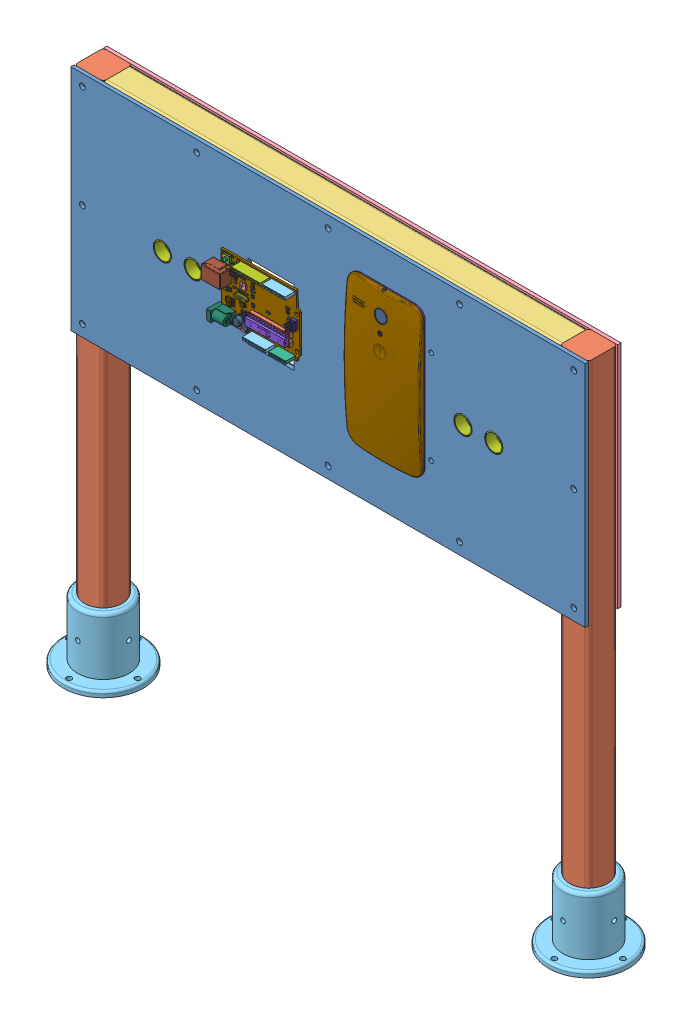
SolidWorks assembly Smart Muisc Player, configuration Default. Lengths in mm.
Overall size (494.6 455 70).
116 component instances, 48 part files, 30 mates.
Components (placement in the parent):
- Front Panel-1: Front Panel [Default] at (-41.307 7.8508 14.9634) size (450 200 3)
- Vetical stand-1: Vetical stand [Default] at (170.993 -341.5339 2.2634) size (25.4 450 25.4)
- Vetical stand-2: Vetical stand [Default] at (-253.607 -341.5339 2.2634) size (25.4 450 25.4)
- Horizontal Stand-2: Horizontal Stand [Default] at (-240.907 95.7661 2.2634) size (399.2 25.4 25.4)
- Horizontal Stand-3: Horizontal Stand [Default] at (-240.907 -78.8339 2.2634) size (399.2 25.4 25.4)
- Back Panel-1: Back Panel [Default] at (-41.307 8.4661 -13.4366) size (450 200 3)
- Base-1: Base [Default] at (170.993 -346.5339 2.2634) size (70 55 70)
- Base-2: Base [Default] at (-253.607 -346.5339 2.2634) size (70 55 70)
- Assem3_1-1: Assem3_1 [Default] at (-169.9461 10.2657 10.8902) x (1 0 0) z (0 -1 0) size (45 18.3 26.12)
  - pin header-1: pin header [Default] at (-4.1109 -10.7267 50.9724) x (0 0 -1) z (1 0 0) size (7.62 4.5 1)
  - UltraSonic-1: UltraSonic [Default] at (-2.8609 -7.9267 1.7996) size (45 15 20)
  - pin header-2: pin header [Default] at (0.8891 -10.7267 50.9724) x (0 0 -1) z (1 0 0) size (7.62 4.5 1)
  - part2_1-1: part2_1 [Default] at (-16.3609 -2.9267 1.7996) x (0.862539 0 -0.505991) z (0.505991 0 0.862539) size (8 0.65 8)
  - pin header-3: pin header [Default] at (-6.6109 -10.7267 50.9724) x (0 0 -1) z (1 0 0) size (7.62 4.5 1)
  - pin header-4: pin header [Default] at (-1.6109 -10.7267 50.9724) x (0 0 -1) z (1 0 0) size (7.62 4.5 1)
  - part2_1-2: part2_1 [Default] at (10.6391 -2.6926 1.7996) x (0.988186 0 -0.153259) z (0.153259 0 0.988186) size (8 0.65 8)
- Assem3_1-2: Assem3_1 [Default] at (93.0539 10.2657 10.8902) x (1 0 0) z (0 -1 0) size (45 18.3 26.12)
  - pin header-1: pin header [Default] at (-4.1109 -10.7267 50.9724) x (0 0 -1) z (1 0 0) size (7.62 4.5 1)
  - UltraSonic-1: UltraSonic [Default] at (-2.8609 -7.9267 1.7996) size (45 15 20)
  - pin header-2: pin header [Default] at (0.8891 -10.7267 50.9724) x (0 0 -1) z (1 0 0) size (7.62 4.5 1)
  - part2_1-1: part2_1 [Default] at (-16.3609 -2.9267 1.7996) x (0.862539 0 -0.505991) z (0.505991 0 0.862539) size (8 0.65 8)
  - pin header-3: pin header [Default] at (-6.6109 -10.7267 50.9724) x (0 0 -1) z (1 0 0) size (7.62 4.5 1)
  - pin header-4: pin header [Default] at (-1.6109 -10.7267 50.9724) x (0 0 -1) z (1 0 0) size (7.62 4.5 1)
  - part2_1-2: part2_1 [Default] at (10.6391 -2.6926 1.7996) x (0.988186 0 -0.153259) z (0.153259 0 0.988186) size (8 0.65 8)
- arduino uno-2: arduino uno [Default] at (-131.6569 -13.9823 20.7834) x (0.013312 -0.999911 0) z (-0.999911 -0.013312 0) size (53.34 15.25 74.93)
  - unoboard blue-1: unoboard blue [Default] at origin size (53.34 1.65 68.58)
  - 47uf CAP Dcase-1: 47uf CAP Dcase [Default] at (-9.4141 0 -18.4991) x (0 0 -1) z (1 0 0) size (6.6 5.81 8)
  - USB SHELL-1: USB SHELL [Default] at (-38.02 0.43 6.35) size (13.72 15.2 16.51)
  - USB core-1: USB core [Default] at (-38.02 0.43 6.35) size (11.3 10.68 15.75)
  - usb top contact-1: usb top contact [Default] at (-36.77 6.52 5.97) size (1 9.67 13.76)
  - usb btm contact-1: usb btm contact [Default] at (-36.77 4.84 5.97) size (1 6.84 11.76)
  - usb btm contact-2: usb btm contact [Default] at (-39.27 4.84 5.97) size (1 6.84 11.76)
  - usb top contact-2: usb top contact [Default] at (-39.27 6.52 5.97) size (1 9.67 13.76)
  - power jack-1: power jack [Default] at (-7.675 0 1.905) size (11.2 15.2 15.9)
  - 47uf CAP Dcase-2: 47uf CAP Dcase [Default] at (-9.4141 0 -25.7132) x (0 0 -1) z (1 0 0) size (6.6 5.81 8)
  - crystal-1: crystal [Default] at (-26.162 0 -18.923) x (1 0 0) z (0 0 -1) size (4 5 11)
  - 2pin_header__02-1: 2pin_header__02 [Default] at (-46.23 0 -15.75) size (5 11.75 2.54)
  - nano - reg-1: nano - reg [Default] at (-17.399 0 -7.747) size (6.5 1.69 8.3)
  - led-1: led [Default] at (-34.29 0 -27.94) x (0 0 1) z (-1 0 0) size (4 0.9 1.55)
  - 2pin_header__02-2: 2pin_header__02 [Default] at (-30.43 0 -64.91) x (0 0 1) z (-1 0 0) size (5 11.75 2.54)
  - dip28-1: dip28 [Default] at (-16.383 1.5 -46.355) x (0 0 -1) z (1 0 0) size (35.48 2.8 10.1)
  - dip socket pin-1: dip socket pin [Default] at (-20.193 4.3 -62.865) x (0 0 -1) z (1 0 0) size (1.7 7.37 1.7)
  - dip socket pin-2: dip socket pin [Default] at (-12.573 4.3 -62.865) x (0 0 -1) z (1 0 0) size (1.7 7.37 1.7)
  - dip socket pin-3: dip socket pin [Default] at (-20.193 4.3 -60.325) x (0 0 -1) z (1 0 0) size (1.7 7.37 1.7)
  - dip socket pin-4: dip socket pin [Default] at (-12.573 4.3 -60.325) x (0 0 -1) z (1 0 0) size (1.7 7.37 1.7)
  - dip socket pin-5: dip socket pin [Default] at (-20.193 4.3 -57.785) x (0 0 -1) z (1 0 0) size (1.7 7.37 1.7)
  - dip socket pin-6: dip socket pin [Default] at (-12.573 4.3 -57.785) x (0 0 -1) z (1 0 0) size (1.7 7.37 1.7)
  - dip socket pin-7: dip socket pin [Default] at (-20.193 4.3 -55.245) x (0 0 -1) z (1 0 0) size (1.7 7.37 1.7)
  - dip socket pin-8: dip socket pin [Default] at (-12.573 4.3 -55.245) x (0 0 -1) z (1 0 0) size (1.7 7.37 1.7)
  - dip socket pin-9: dip socket pin [Default] at (-20.193 4.3 -52.705) x (0 0 -1) z (1 0 0) size (1.7 7.37 1.7)
  - dip socket pin-10: dip socket pin [Default] at (-12.573 4.3 -52.705) x (0 0 -1) z (1 0 0) size (1.7 7.37 1.7)
  - dip socket pin-11: dip socket pin [Default] at (-20.193 4.3 -50.165) x (0 0 -1) z (1 0 0) size (1.7 7.37 1.7)
  - dip socket pin-12: dip socket pin [Default] at (-12.573 4.3 -50.165) x (0 0 -1) z (1 0 0) size (1.7 7.37 1.7)
  - dip socket pin-13: dip socket pin [Default] at (-20.193 4.3 -47.625) x (0 0 -1) z (1 0 0) size (1.7 7.37 1.7)
  - dip socket pin-14: dip socket pin [Default] at (-12.573 4.3 -47.625) x (0 0 -1) z (1 0 0) size (1.7 7.37 1.7)
  - dip socket pin-15: dip socket pin [Default] at (-20.193 4.3 -45.085) x (0 0 -1) z (1 0 0) size (1.7 7.37 1.7)
  - dip socket pin-16: dip socket pin [Default] at (-12.573 4.3 -45.085) x (0 0 -1) z (1 0 0) size (1.7 7.37 1.7)
  - dip socket pin-17: dip socket pin [Default] at (-20.193 4.3 -42.545) x (0 0 -1) z (1 0 0) size (1.7 7.37 1.7)
  - dip socket pin-18: dip socket pin [Default] at (-12.573 4.3 -42.545) x (0 0 -1) z (1 0 0) size (1.7 7.37 1.7)
  - dip socket pin-19: dip socket pin [Default] at (-20.193 4.3 -40.005) x (0 0 -1) z (1 0 0) size (1.7 7.37 1.7)
  - dip socket pin-20: dip socket pin [Default] at (-12.573 4.3 -40.005) x (0 0 -1) z (1 0 0) size (1.7 7.37 1.7)
  - dip socket pin-21: dip socket pin [Default] at (-20.193 4.3 -37.465) x (0 0 -1) z (1 0 0) size (1.7 7.37 1.7)
  - dip socket pin-22: dip socket pin [Default] at (-12.573 4.3 -37.465) x (0 0 -1) z (1 0 0) size (1.7 7.37 1.7)
  - dip socket pin-23: dip socket pin [Default] at (-20.193 4.3 -34.925) x (0 0 -1) z (1 0 0) size (1.7 7.37 1.7)
  - dip socket pin-24: dip socket pin [Default] at (-12.573 4.3 -34.925) x (0 0 -1) z (1 0 0) size (1.7 7.37 1.7)
  - dip socket pin-25: dip socket pin [Default] at (-20.193 4.3 -32.385) x (0 0 -1) z (1 0 0) size (1.7 7.37 1.7)
  - dip socket pin-26: dip socket pin [Default] at (-12.573 4.3 -32.385) x (0 0 -1) z (1 0 0) size (1.7 7.37 1.7)
  - dip socket pin-27: dip socket pin [Default] at (-20.193 4.3 -29.845) x (0 0 -1) z (1 0 0) size (1.7 7.37 1.7)
  - dip socket pin-28: dip socket pin [Default] at (-12.573 4.3 -29.845) x (0 0 -1) z (1 0 0) size (1.7 7.37 1.7)
  - 2pin_header__02-3: 2pin_header__02 [Default] at (-27.89 0 -64.91) x (0 0 1) z (-1 0 0) size (5 11.75 2.54)
  - 2pin_header__02-4: 2pin_header__02 [Default] at (-25.35 0 -64.91) x (0 0 1) z (-1 0 0) size (5 11.75 2.54)
  - 2pin_header__02-5: 2pin_header__02 [Default] at (-46.23 0 -18.29) size (5 11.75 2.54)
  - 2pin_header__02-6: 2pin_header__02 [Default] at (-46.23 0 -20.83) size (5 11.75 2.54)
  - atmega16u2-1: atmega16u2 [Default] at (-34.671 0.06 -20) x (1 0 0) z (0 0 -1) size (5.5 1.01 5.5)
  - led-2: led [Default] at (-36.83 0 -27.94) x (0 0 1) z (-1 0 0) size (4 0.9 1.55)
  - led-3: led [Default] at (-42.037 0 -27.94) x (0 0 1) z (-1 0 0) size (4 0.9 1.55)
  - led-4: led [Default] at (-36.576 0 -58.42) x (0 0 1) z (-1 0 0) size (4 0.9 1.55)
  - 8 PORT HEADER-1: 8 PORT HEADER [Default] at (-50.8 0 -45.72) x (0 0 -1) z (1 0 0) size (20.32 10.51 2.41)
  - 8 PORT HEADER-2: 8 PORT HEADER [Default] at (-2.54 0 -27.94) x (0 0 -1) z (1 0 0) size (20.32 10.51 2.41)
  - 6 PORT HEADER-1: 6 PORT HEADER [Default] at (-2.54 0 -50.8) x (0 0 -1) z (1 0 0) size (15.24 10.51 2.41)
  - 10 PORT HEADER-1: 10 PORT HEADER [Default] at (-50.8 0 -18.796) x (0 0 -1) z (1 0 0) size (25.4 10.51 2.41)
  - ATMEL328P-1: ATMEL328P [Default] at (-16.383 4.3 -46.355) x (0 0 -1) z (1 0 0) size (35 7.27 7.87)
  - 102 RESISTOR PACK-1: 102 RESISTOR PACK [Default] at (-33.782 0 -58.42) size (3.2 0.51 3)
  - 102 RESISTOR PACK-2: 102 RESISTOR PACK [Default] at (-39.37 0 -27.94) size (3.2 0.51 3)
  - 103 RESISTOR PACK-1: 103 RESISTOR PACK [Default] at (-23.876 0 -27.94) size (3.2 0.51 3)
  - 220 RESISTOR PACK-1: 220 RESISTOR PACK [Default] at (-36.83 0 -12.827) size (3.2 0.51 3)
  - 16mhz crystal - measured-1: 16mhz crystal - measured [Default] at (-24.892 0 -41.275) x (0 0 -1) z (1 0 0) size (3.4 0.8 2)
  - PADS001-1: PADS001 [Default] at (-39.878 0.1 -18.288) x (-1 0 0) z (0 0 1) size (4.54 0.1 4.54)
  - 603 cap on pad-1: 603 cap on pad [Default] at (-44.45 0 -27.94) x (0 0 -1) z (1 0 0) size (2.76 0.91 1.02)
  - ssot3-1: ssot3 [Default] at (-26.5 0 -8.128) x (-1 0 0) z (0 0 -1) size (3 1.13 3.09)
  - mf-msmf050-2-1: mf-msmf050-2 [Default] at (-26.5 0 -4.064) size (5.76 1.02 3.72)
  - 603 cap on pad-2: 603 cap on pad [Default] at (-29.845 0 -27.94) x (0 0 -1) z (1 0 0) size (2.76 0.91 1.02)
  - 603 cap on pad-3: 603 cap on pad [Default] at (-31.496 0 -27.94) x (0 0 -1) z (1 0 0) size (2.76 0.91 1.02)
  - lmv358-1: lmv358 [Default] at (-15.24 0 -21.971) x (0 0 -1) z (1 0 0) size (3.7 1.4 2.9)
  - 603 cap on pad-4: 603 cap on pad [Default] at (-15.24 0 -18.415) size (2.76 0.91 1.02)
  - 603 cap on pad-5: 603 cap on pad [Default] at (-29.845 0 -12.065) x (0 0 1) z (-1 0 0) size (2.76 0.91 1.02)
  - 603 cap on pad-6: 603 cap on pad [Default] at (-29.591 0 -22.352) x (0 0 1) z (-1 0 0) size (2.76 0.91 1.02)
  - 603 cap on pad-7: 603 cap on pad [Default] at (-29.591 0 -16.002) x (0 0 1) z (-1 0 0) size (2.76 0.91 1.02)
  - 603 cap on pad-8: 603 cap on pad [Default] at (-41.91 0 -12.7) x (0 0 1) z (-1 0 0) size (2.76 0.91 1.02)
  - lp2985dgkr-1: lp2985dgkr [Default] at (-20.32 0 -19.05) x (0 0 -1) z (1 0 0) size (5.85 1.1 3)
  - cd1206 diode-1: cd1206 diode [Default] at (-27.94 0 -59.436) x (0 0 -1) z (1 0 0) size (2.09 0.96 5)
  - cd1206 diode-2: cd1206 diode [Default] at (-46.228 0 -13.081) x (0 0 1) z (-1 0 0) size (2.09 0.96 5)
  - 603 resistor-1: 603 resistor [Default] at (-29.591 0 -19.05) x (0 0 1) z (-1 0 0) size (2.36 0.62 1.03)
  - blm21-1: blm21 [Default] at (-45.085 0 -7.62) x (0 0 -1) z (1 0 0) size (2.78 0.95 1.32)
  - m7 diode-1: m7 diode [Default] at (-2.794 0 -21.59) x (0 0 -1) z (1 0 0) size (6.66 2.35 2.5)
  - MLC0603-1: MLC0603 [Default] at (-33.655 0 -12.827) x (0 0 -1) z (1 0 0) size (2.36 0.6 1.03)
  - MLC0603-2: MLC0603 [Default] at (-39.37 0 -12.827) x (0 0 -1) z (1 0 0) size (2.36 0.6 1.03)
  - RESET CORE-1: RESET CORE [Default] at (-49.403 0.1 -6.35) x (-1 0 0) z (0 0 -1) size (6.2 3.1 9.6)
  - RESET-1: RESET [Default] at (-49.403 0.1 -6.35) x (0 0 1) z (-1 0 0) size (7.3 2 6.2)
- moto_g-1: moto_g [Default] at (12.461 16.4193 21.7634) x (0 0 -1) z (1 0 0) size (9.15 140.46 73.62)
  - BODY_MOTOG-1: BODY_MOTOG [Default] at origin size (8.5 129.9 66.1)
  - TAPA_MOTOG-1: TAPA_MOTOG [Default] at origin size (6.68 140.46 73.62)
  - CRISTAL_CAMARA-1: CRISTAL_CAMARA [Default] at origin size (1.16 10.32 10.31)
  - CRISTAL_PANTALLA-1: CRISTAL_PANTALLA [Default] at origin size (1 123.91 59.91)
    - CRISTAL_MOTOG-1: CRISTAL_MOTOG [Default] at origin size (1 123.91 59.91)
    - PANTALLA_MOTOG-1: PANTALLA_MOTOG [Default] at origin size (0.5 100.28 58)
Mates (geometry in assembly coordinates):
- Coincident1: coincident anti-aligned: plane of Front Panel-1 through (183.693 108.4661 14.9634) normal (0 0 -1); plane of Vetical stand-1 through (158.293 108.4661 14.9634) normal (0 0 1)
- Coincident2: coincident aligned: plane of Front Panel-1 through (-266.307 108.4661 17.9634) normal (0 1 0); plane of Vetical stand-1 through (183.693 108.4661 -10.4366) normal (0 1 0)
- Coincident3: coincident aligned: plane of Front Panel-1 through (183.693 -91.5339 17.9634) normal (1 0 0); plane of Vetical stand-1 through (183.693 108.4661 14.9634) normal (1 0 0)
- Coincident4: coincident anti-aligned: plane of Front Panel-1 through (183.693 108.4661 14.9634) normal (0 0 -1); plane of Vetical stand-2 through (-266.307 108.4661 14.9634) normal (0 0 1)
- Coincident5: coincident aligned: plane of Front Panel-1 through (-266.307 -91.5339 17.9634) normal (-1 0 0); plane of Vetical stand-2 through (-266.307 108.4661 14.9634) normal (-1 0 0)
- Coincident6: coincident aligned: plane of Front Panel-1 through (-266.307 108.4661 17.9634) normal (0 1 0); plane of Vetical stand-2 through (-240.907 108.4661 -10.4366) normal (0 1 0)
- Coincident7: coincident anti-aligned: plane of Front Panel-1 through (183.693 108.4661 14.9634) normal (0 0 -1); plane of Horizontal Stand-2 through (158.293 83.0661 14.9634) normal (0 0 1)
- Coincident8: coincident anti-aligned: plane of Vetical stand-2 through (-240.907 108.4661 14.9634) normal (1 0 0); plane of Horizontal Stand-2 through (-240.907 108.4661 -10.4366) normal (-1 0 0)
- Coincident9: coincident aligned: plane of Front Panel-1 through (-266.307 108.4661 17.9634) normal (0 1 0); plane of Horizontal Stand-2 through (158.293 108.4661 14.9634) normal (0 1 0)
- Coincident11: coincident anti-aligned: plane of Front Panel-1 through (183.693 108.4661 14.9634) normal (0 0 -1); plane of Horizontal Stand-3 through (158.293 -91.5339 14.9634) normal (0 0 1)
- Coincident12: coincident anti-aligned: plane of Vetical stand-1 through (158.293 108.4661 14.9634) normal (-1 0 0); plane of Horizontal Stand-3 through (158.293 -66.1339 -10.4366) normal (1 0 0)
- Coincident13: coincident aligned: plane of Front Panel-1 through (-266.307 -91.5339 17.9634) normal (0 -1 0); plane of Horizontal Stand-3 through (158.293 -91.5339 14.9634) normal (0 -1 0)
- Coincident14: coincident anti-aligned: plane of Vetical stand-1 through (158.293 108.4661 -10.4366) normal (0 0 -1); plane of Back Panel-1 through (183.693 108.4661 -10.4366) normal (0 0 1)
- Coincident15: coincident aligned: plane of Vetical stand-1 through (183.693 108.4661 14.9634) normal (1 0 0); plane of Back Panel-1 through (183.693 -91.5339 -10.4366) normal (1 0 0)
- Coincident16: coincident aligned: plane of Horizontal Stand-2 through (158.293 108.4661 14.9634) normal (0 1 0); plane of Back Panel-1 through (-266.307 108.4661 -10.4366) normal (0 1 0)
- Coincident17: coincident anti-aligned: plane of Vetical stand-1 through (183.693 -341.5339 -10.4366) normal (0 -1 0); plane of Base-1 through (170.993 -341.5339 2.2634) normal (0 1 0)
- Coincident18: coincident: plane of Vetical stand-1 through (183.693 108.4661 14.9634) normal (1 0 0); plane of Base-1 through (183.693 -291.5339 14.9634) normal (-1 0 0)
- Coincident19: coincident: plane of Vetical stand-1 through (158.293 108.4661 14.9634) normal (0 0 1); plane of Base-1 through (158.293 -291.5339 14.9634) normal (0 0 -1)
- Coincident20: coincident: plane of Vetical stand-2 through (-266.307 108.4661 -10.4366) normal (0 0 -1); plane of Base-2 through (-266.307 -291.5339 -10.4366) normal (0 0 1)
- Coincident21: coincident: plane of Vetical stand-2 through (-266.307 108.4661 14.9634) normal (-1 0 0); plane of Base-2 through (-266.307 -291.5339 14.9634) normal (1 0 0)
- Coincident22: coincident anti-aligned: plane of Vetical stand-2 through (-240.907 -341.5339 -10.4366) normal (0 -1 0); plane of Base-2 through (-253.607 -341.5339 2.2634) normal (0 1 0)
- Concentric1: concentric aligned: cylinder of Front Panel-1 through (-186.307 8.4661 17.9634) axis (0 0 -1) radius 8; cylinder of Assem3_1-1/UltraSonic-1 through (-186.307 8.4661 17.9634) axis (0 0 -1) radius 8
- Tangent1: tangent: plane of Front Panel-1 through (183.693 108.4661 17.9634) normal (0 0 1); face of Assem3_1-1/UltraSonic-1
- Concentric2: concentric aligned: cylinder of Front Panel-1 through (-159.307 8.4661 17.9634) axis (0 0 -1) radius 8; cylinder of Assem3_1-1/UltraSonic-1 through (-159.307 8.4661 17.9634) axis (0 0 -1) radius 8
- Concentric3: concentric aligned: cylinder of Front Panel-1 through (76.693 8.4661 17.9634) axis (0 0 -1) radius 8; cylinder of Assem3_1-2/UltraSonic-1 through (76.693 8.4661 17.9634) axis (0 0 -1) radius 8
- Concentric4: concentric aligned: cylinder of Front Panel-1 through (103.693 8.4661 17.9634) axis (0 0 -1) radius 8; cylinder of Assem3_1-2/UltraSonic-1 through (103.693 8.4661 17.9634) axis (0 0 -1) radius 8
- Tangent3: tangent: plane of Front Panel-1 through (183.693 108.4661 17.9634) normal (0 0 1); face of Assem3_1-2/UltraSonic-1
- Coincident23: coincident anti-aligned: plane of Front Panel-1 through (183.693 108.4661 17.9634) normal (0 0 1); circle of arduino uno-2/dip socket pin-27
- Coincident24: coincident anti-aligned: plane of Front Panel-1 through (183.693 108.4661 17.9634) normal (0 0 1); plane of moto_g-1/CRISTAL_PANTALLA-1/CRISTAL_MOTOG-1 through (43.6159 -48.0156 17.9634) normal (0 0 -1)
- Concentric8: concentric: cylinder of Front Panel-1 through (-65.7242 -5.4839 17.9634) axis (0 0 -1) radius 1.75; cylinder of arduino uno-2/unoboard blue-1 through (-65.7242 -5.4839 19.1334) axis (0 0 1) radius 1.5875
